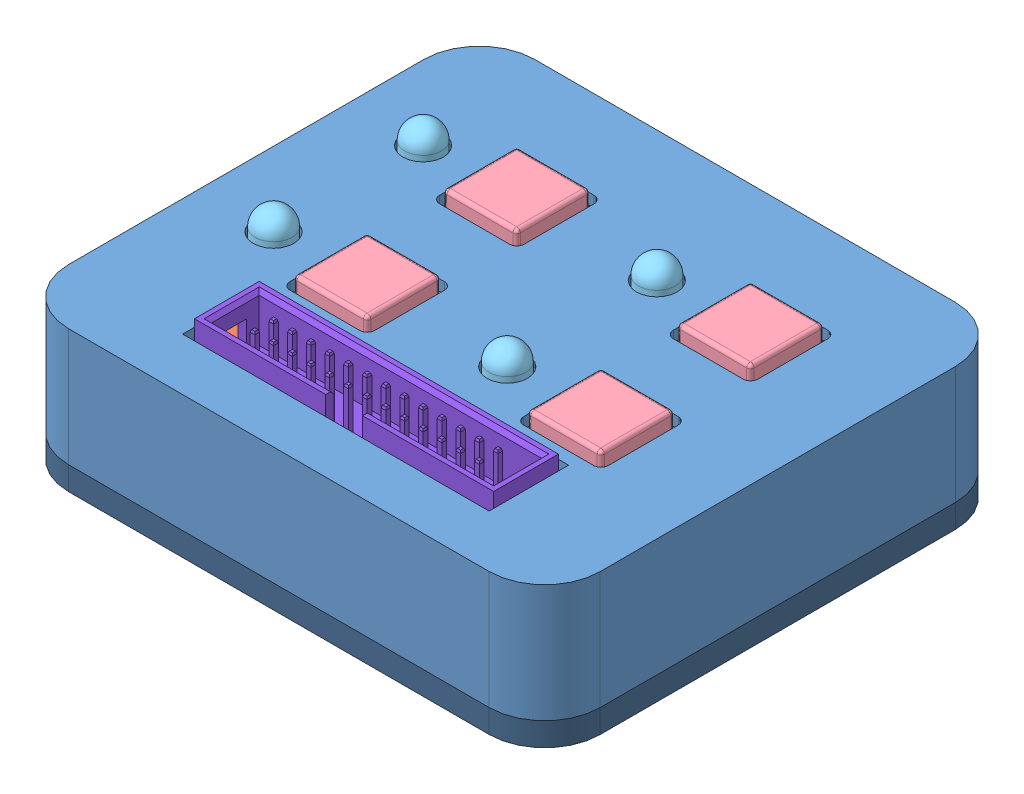
SolidWorks assembly Assembled, configuration Default. Lengths in mm.
Overall size (72.23 24.56 63.34).
41 component instances, 11 part files, 23 mates.
Components (placement in the parent):
- case-1: case [Default] at (-20.9628 0 5.1392) x (-1 0 0) z (0 0 1) size (72.23 16 63.34)
- Assembled PCB-1: Assembled PCB [Default] at (2.5795 -32.7955 58.1532) x (-1 0 0) z (0 0 -1) size (62.23 14.18 53.34)
  - PCB-1: PCB [Default] at (23.5423 23.7207 53.0141) size (62.23 1.57 53.34)
  - Button Assembly-1: Button Assembly [Default] at (104.7843 22.09 18.5104) size (12 10.4 12)
    - button-1: button [Default] at (-99.657 3.2054 48.4737) size (12 8.9 12)
    - Cap-2: Cap [Default] at (-99.657 12.0054 48.4737) size (10 4.5 10)
  - Button Assembly-2: Button Assembly [Default] at (104.7843 22.09 -1.8054) size (12 10.4 12)
    - button-1: button [Default] at (-99.657 3.2054 48.4737) size (12 8.9 12)
    - Cap-2: Cap [Default] at (-99.657 12.0054 48.4737) size (10 4.5 10)
  - Button Assembly-3: Button Assembly [Default] at (136.5343 22.09 18.5104) size (12 10.4 12)
    - button-1: button [Default] at (-99.657 3.2054 48.4737) size (12 8.9 12)
    - Cap-2: Cap [Default] at (-99.657 12.0054 48.4737) size (10 4.5 10)
  - Button Assembly-4: Button Assembly [Default] at (136.5343 22.09 -1.8054) size (12 10.4 12)
    - button-1: button [Default] at (-99.657 3.2054 48.4737) size (12 8.9 12)
    - Cap-2: Cap [Default] at (-99.657 12.0054 48.4737) size (10 4.5 10)
  - LED short-1: LED short [Default] at (17.8273 29.3722 66.9841) x (-1 0 0) z (0 0 -1) size (5.45 13.1 5.9)
    - LED Head-1: LED Head [Default] at origin size (5.45 8.6 5.9)
    - LED Leads-1: LED Leads [Default] at (0 -5.1452 0) size (4.04 8 0.3)
  - LED short-3: LED short [Default] at (17.8273 29.3722 46.6641) x (-1 0 0) z (0 0 -1) size (5.45 13.1 5.9)
    - LED Head-1: LED Head [Default] at origin size (5.45 8.6 5.9)
    - LED Leads-1: LED Leads [Default] at (0 -5.1452 0) size (4.04 8 0.3)
  - LED short-4: LED short [Default] at (49.5773 29.3722 46.6641) x (-1 0 0) z (0 0 -1) size (5.45 13.1 5.9)
    - LED Head-1: LED Head [Default] at origin size (5.45 8.6 5.9)
    - LED Leads-1: LED Leads [Default] at (0 -5.1452 0) size (4.04 8 0.3)
  - LED short-5: LED short [Default] at (49.5773 29.3722 66.9841) x (-1 0 0) z (0 0 -1) size (5.45 13.1 5.9)
    - LED Head-1: LED Head [Default] at origin size (5.45 8.6 5.9)
    - LED Leads-1: LED Leads [Default] at (0 -5.1452 0) size (4.04 8 0.3)
  - Resistor .4-1: Resistor .4 [Default] at (5.1273 26.7955 56.8241) size (10.67 6.22 2.29)
  - Resistor .4-2: Resistor .4 [Default] at (5.1273 26.7955 75.8741) size (10.67 6.22 2.29)
  - Resistor .4-3: Resistor .4 [Default] at (36.8773 26.7955 56.8241) x (-1 0 0) z (0 0 -1) size (10.67 6.22 2.29)
  - Resistor .4-4: Resistor .4 [Default] at (36.8773 26.7955 75.8741) x (-1 0 0) z (0 0 -1) size (10.67 6.22 2.29)
  - header-1: header [Default] at (22.9073 25.3955 33.9641) x (-1 0 0) z (0 0 -1) size (40.64 11.9 8.8)
- spacer-1: spacer [Default] at (-49.5378 -15.4248 29.2692) x (-1 0 0) z (0 0 -1) size (4.76 6.35 4.76)
- spacer-2: spacer [Default] at (7.6122 -15.4248 29.2692) x (-1 0 0) z (0 0 -1) size (4.76 6.35 4.76)
- spacer-3: spacer [Default] at (7.6122 -15.4248 -18.9908) x (-1 0 0) z (0 0 -1) size (4.76 6.35 4.76)
- spacer-4: spacer [Default] at (-49.5378 -15.4248 -18.9908) x (-1 0 0) z (0 0 -1) size (4.76 6.35 4.76)
- Bottom-1: Bottom [Default] at (-84.4716 -19.175 -98.8281) x (-1 0 0) z (0 0 -1) size (72.23 3.17 63.34)
- Screw-1: Screw [90184A110] at (7.6122 -19.175 -18.9908) x (0.485376 0 -0.874306) z (0 -1 0) size (5.56 5.82 20.7)
- Screw-2: Screw [90184A110] at (7.6122 -19.175 29.2692) x (0.485376 0 -0.874306) z (0 -1 0) size (5.56 5.82 20.7)
- Screw-3: Screw [90184A110] at (-49.5378 -19.175 29.2692) x (0.485376 0 -0.874306) z (0 -1 0) size (5.56 5.82 20.7)
- Screw-4: Screw [90184A110] at (-49.5378 -19.175 -18.9908) x (0.485376 0 -0.874306) z (0 -1 0) size (5.56 5.82 20.7)
Mates (geometry in assembly coordinates):
- Concentric1: concentric aligned: cylinder of case-1 through (-49.5378 -7.5 29.2692) axis (0 1 0) radius 1; cylinder of Assembled PCB-1/PCB-1 through (-49.5378 -9.0748 29.2692) axis (0 1 0) radius 1.5
- Concentric2: concentric aligned: cylinder of case-1 through (-49.5378 -7.5 -18.9908) axis (0 1 0) radius 1; cylinder of Assembled PCB-1/PCB-1 through (-49.5378 -9.0748 -18.9908) axis (0 1 0) radius 1.5
- Concentric3: concentric aligned: cylinder of case-1 through (7.6122 -7.5 -18.9908) axis (0 1 0) radius 1; cylinder of Assembled PCB-1/PCB-1 through (7.6122 -9.0748 -18.9908) axis (0 1 0) radius 1.5
- Coincident1: coincident anti-aligned: plane of case-1 through (7.6122 -7.5 29.2692) normal (0 -1 0); plane of Assembled PCB-1/PCB-1 through (-49.5378 -7.5 29.2692) normal (0 1 0)
- Coincident2: coincident anti-aligned: plane of Assembled PCB-1/PCB-1 through (-49.5378 -9.0748 29.2692) normal (0 -1 0); plane of spacer-1 through (-49.5378 -9.0748 29.2692) normal (0 1 0)
- Concentric5: concentric anti-aligned: cylinder of case-1 through (-49.5378 -7.5 29.2692) axis (0 1 0) radius 1; cylinder of spacer-1 through (-49.5378 -9.0748 29.2692) axis (0 -1 0) radius 1.4605
- Coincident3: coincident anti-aligned: plane of Assembled PCB-1/PCB-1 through (-49.5378 -9.0748 29.2692) normal (0 -1 0); plane of spacer-2 through (7.6122 -9.0748 29.2692) normal (0 1 0)
- Concentric6: concentric anti-aligned: cylinder of case-1 through (7.6122 -7.5 29.2692) axis (0 1 0) radius 1; cylinder of spacer-2 through (7.6122 -9.0748 29.2692) axis (0 -1 0) radius 1.4605
- Coincident4: coincident anti-aligned: plane of Assembled PCB-1/PCB-1 through (-49.5378 -9.0748 29.2692) normal (0 -1 0); plane of spacer-3 through (7.6122 -9.0748 -18.9908) normal (0 1 0)
- Concentric7: concentric anti-aligned: cylinder of case-1 through (7.6122 -7.5 -18.9908) axis (0 1 0) radius 1; cylinder of spacer-3 through (7.6122 -9.0748 -18.9908) axis (0 -1 0) radius 1.4605
- Coincident5: coincident anti-aligned: plane of Assembled PCB-1/PCB-1 through (-49.5378 -9.0748 29.2692) normal (0 -1 0); plane of spacer-4 through (-49.5378 -9.0748 -18.9908) normal (0 1 0)
- Concentric8: concentric anti-aligned: cylinder of case-1 through (-49.5378 -7.5 -18.9908) axis (0 1 0) radius 1; cylinder of spacer-4 through (-49.5378 -9.0748 -18.9908) axis (0 -1 0) radius 1.4605
- Coincident6: coincident anti-aligned: line of case-1 through (-57.0778 -16 29.2692) axis (0 0 -1); line of Bottom-1 through (-57.0778 -16 -18.9908) axis (0 0 1)
- Coincident7: coincident anti-aligned: line of case-1 through (-49.5378 -16 -26.5308) axis (1 0 0); line of Bottom-1 through (7.6122 -16 -26.5308) axis (-1 0 0)
- Concentric9: concentric aligned: cylinder of case-1 through (7.6122 -7.5 -18.9908) axis (0 1 0) radius 1; circle of Screw-1
- Coincident8: coincident anti-aligned: plane of Bottom-1 through (-84.4716 -19.175 -98.8281) normal (0 -1 0); plane of Screw-1 through (7.6122 -19.175 -18.9908) normal (0 1 0)
- Coincident9: coincident anti-aligned: plane of Bottom-1 through (-84.4716 -19.175 -98.8281) normal (0 -1 0); plane of Screw-2 through (7.6122 -19.175 29.2692) normal (0 1 0)
- Concentric10: concentric aligned: cylinder of case-1 through (7.6122 -7.5 29.2692) axis (0 1 0) radius 1; circle of Screw-2
- Concentric11: concentric aligned: cylinder of case-1 through (-49.5378 -7.5 29.2692) axis (0 1 0) radius 1; circle of Screw-3
- Coincident10: coincident anti-aligned: plane of Bottom-1 through (-84.4716 -19.175 -98.8281) normal (0 -1 0); plane of Screw-3 through (-49.5378 -19.175 29.2692) normal (0 1 0)
- Concentric12: concentric aligned: cylinder of case-1 through (-49.5378 -7.5 -18.9908) axis (0 1 0) radius 1; circle of Screw-4
- Coincident11: coincident anti-aligned: plane of Bottom-1 through (-84.4716 -19.175 -98.8281) normal (0 -1 0); plane of Screw-4 through (-49.5378 -19.175 -18.9908) normal (0 1 0)
- Coincident12: coincident aligned: plane of case-1 through (-20.9628 0 5.1392) normal (0 1 0); plane of assembly through (0 0 0) normal (0 1 0)
